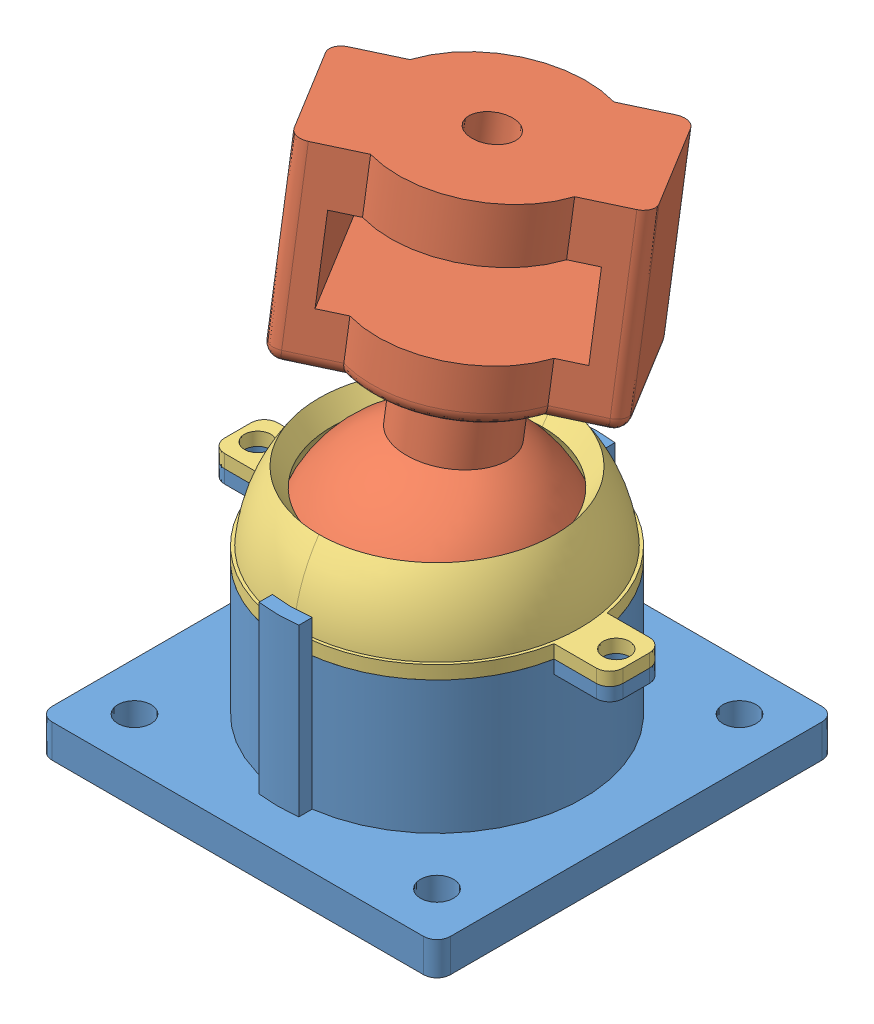
SolidWorks assembly TestBallJoint, configuration Default. Lengths in mm.
Overall size (60 82.65 61.88).
4 component instances, 3 part files, 7 mates.
Components (placement in the parent):
- Socket-1: Socket [Default] at origin size (60 30 60)
- Ball-1: Ball [Default] at (1.9013 71.5329 -5.2173) x (0.840103 -0.09422 -0.534181) z (0.540908 0.071857 0.838007) size (40 72.86 36)
- SocketCap-1: SocketCap [Default] at (0 25 0) size (30 12.32 44)
- SocketCap-2: SocketCap [Default] at (0 25 0) x (-1 0 0) z (0 0 -1) size (30 12.32 44)
Mates (geometry in assembly coordinates):
- Concentric1: concentric: sphere of Socket-1; sphere of Ball-1
- Coincident1: coincident anti-aligned: plane of Socket-1 through (0 25 0) normal (0 1 0); plane of SocketCap-1 through (0 25 0) normal (0 -1 0)
- Concentric3: concentric anti-aligned: cylinder of Socket-1 through (27 23 0) axis (0 1 0) radius 2; cylinder of SocketCap-1 through (27 27 0) axis (0 -1 0) radius 2
- Concentric4: concentric: sphere of Ball-1; sphere of SocketCap-1
- Concentric5: concentric anti-aligned: cylinder of Socket-1 through (-27 23 0) axis (0 1 0) radius 2; cylinder of SocketCap-2 through (-27 27 0) axis (0 -1 0) radius 2
- Coincident2: coincident anti-aligned: plane of Socket-1 through (0 25 0) normal (0 1 0); plane of SocketCap-2 through (0 25 0) normal (0 -1 0)
- Concentric6: concentric: sphere of Ball-1; sphere of SocketCap-2
